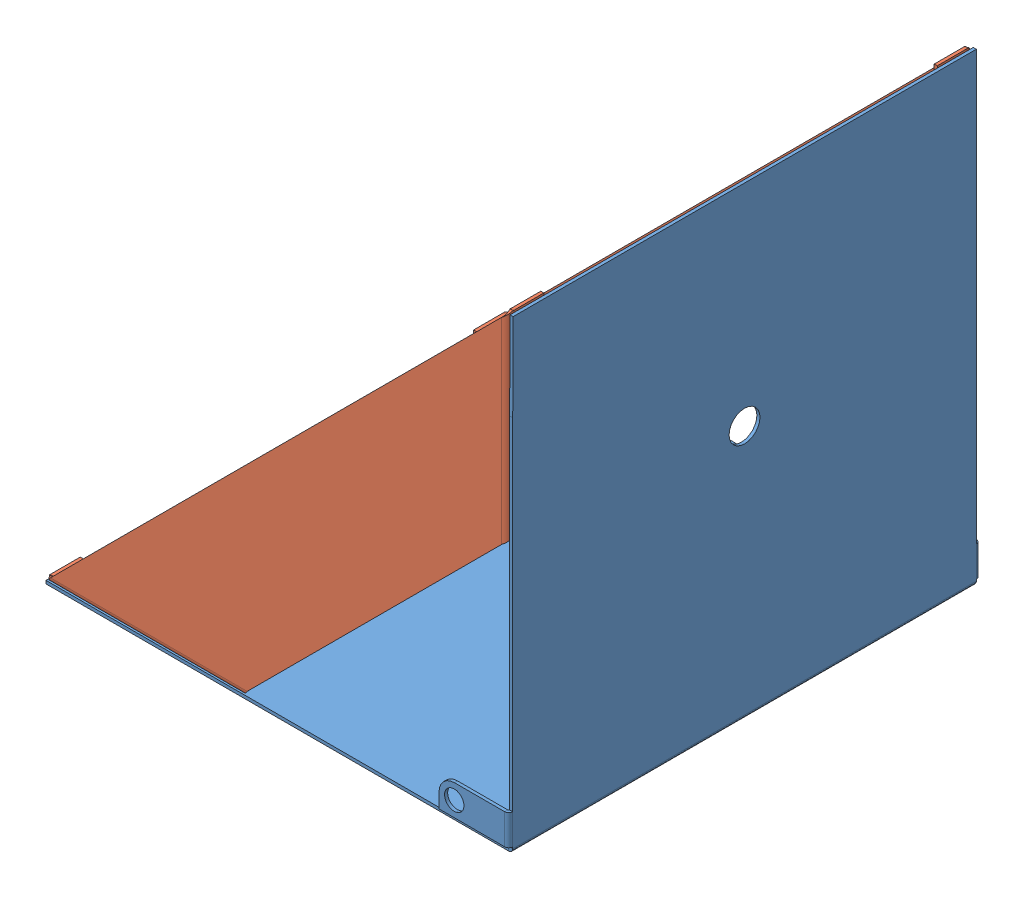
SolidWorks assembly MainBodyAssem, configuration Default. Lengths in mm.
Overall size (383.55 383.55 387.55).
3 component instances, 2 part files, 6 mates.
Components (placement in the parent):
- MainBody-1: MainBody [Default] at (-11.3224 52.2437 481.7014) size (383.54 381.86 387.55)
- DiagonalHolder-1: DiagonalHolder [Default] at (369.6776 433.2437 480.5768) x (0 -1 0) z (1 0 0) size (381.01 29.58 381.01)
- DiagonalHolder-2: DiagonalHolder [Default] at (-11.3224 52.2437 103.2414) x (1 0 0) z (0 -1 0) size (381.01 29.58 381.01)
Mates (geometry in assembly coordinates):
- Coincident1: coincident anti-aligned: plane of MainBody-1 through (369.6776 66.6749 526.1514) normal (-1 0 0); plane of DiagonalHolder-1 through (369.6776 433.2437 478.9416) normal (1 0 0)
- Coincident2: coincident: plane of MainBody-1 through (372.2176 359.7238 481.7014) normal (0 0.005025 0.999987); plane of DiagonalHolder-1 through (369.6776 433.2437 483.1168) normal (0 0 1)
- Coincident6: coincident: plane of MainBody-1 through (385.7876 52.2437 526.1514) normal (0 1 0); plane of DiagonalHolder-1 through (369.6776 52.2437 859.9416) normal (0 -1 0)
- Coincident8: coincident anti-aligned: plane of MainBody-1 through (369.6776 66.6749 526.1514) normal (-1 0 0); plane of DiagonalHolder-2 through (369.6776 52.2437 -276.1234) normal (1 0 0)
- Coincident9: coincident aligned: plane of MainBody-1 through (372.2176 79.3749 100.7014) normal (0 0 -1); plane of DiagonalHolder-2 through (-11.3224 52.2437 100.7014) normal (0 0 -1)
- Coincident10: coincident anti-aligned: plane of MainBody-1 through (385.7876 52.2437 526.1514) normal (0 1 0); plane of DiagonalHolder-2 through (-11.3224 52.2437 104.8766) normal (0 -1 0)
